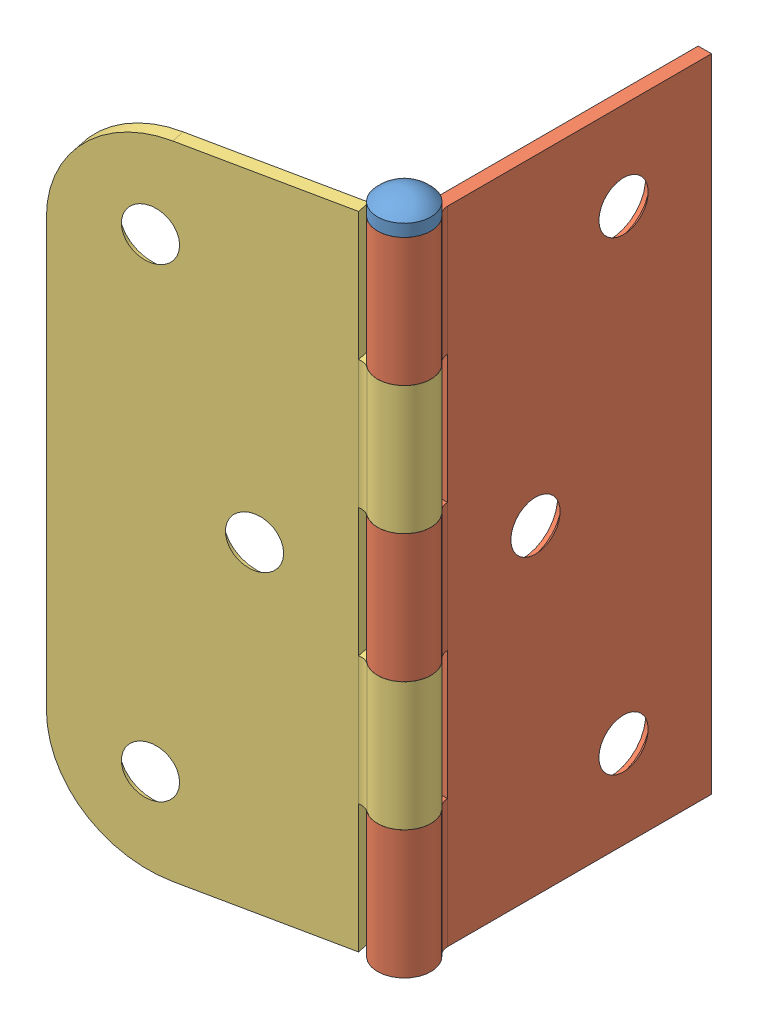
SolidWorks assembly Hinge Simple, configuration Default. Lengths in mm.
Overall size (38.6 79.13 45.12).
3 component instances, 3 part files, 6 mates.
Components (placement in the parent):
- Hinge Pin-1: Hinge Pin [Default] at origin size (6.35 79.13 6.35)
- Hinge Side 1-1: Hinge Side 1 [Default] at (0 -11.2995 0) size (6.35 76.2 38.1)
- Hinge Side 2-1: Hinge Side 2 [Default] at (0 -11.2995 0) x (0.202774 0 0.979226) z (0.979226 0 -0.202774) size (6.35 76.2 38.1)
Mates (geometry in assembly coordinates):
- Concentric1: concentric aligned: cylinder of Hinge Pin-1 through (0 -49.3995 0) axis (0 -1 0) radius 1.5875; cylinder of Hinge Side 1-1 through (0 26.8005 0) axis (0 -1 0) radius 1.5875
- Coincident1: coincident anti-aligned: plane of Hinge Pin-1 through (0 26.8005 1.5875) normal (0 -1 0); plane of Hinge Side 1-1 through (0 26.8005 0) normal (0 1 0)
- Concentric2: concentric anti-aligned: cylinder of Hinge Pin-1 through (0 -49.3995 0) axis (0 -1 0) radius 1.5875; cylinder of Hinge Side 2-1 through (0 -49.3995 0) axis (0 1 0) radius 1.5875
- Coincident2: coincident anti-aligned: plane of Hinge Side 1-1 through (-3.175 11.5605 -3.5498) normal (0 -1 0); plane of Hinge Side 2-1 through (-4.1198 11.5605 -2.3892) normal (0 1 0)
- Coincident3: coincident aligned: plane of Hinge Side 1-1 through (0 -11.2995 0) normal (1 0 0); plane of assembly through (0 0 0) normal (1 0 0)
- LimitAngle3: limit planar angle = 1.774986 rad anti-aligned: plane of Hinge Side 1-1 through (0 26.8005 0) normal (-1 0 0); plane of Hinge Side 2-1 through (0 -49.3995 0) normal (-0.202774 0 -0.979226)
